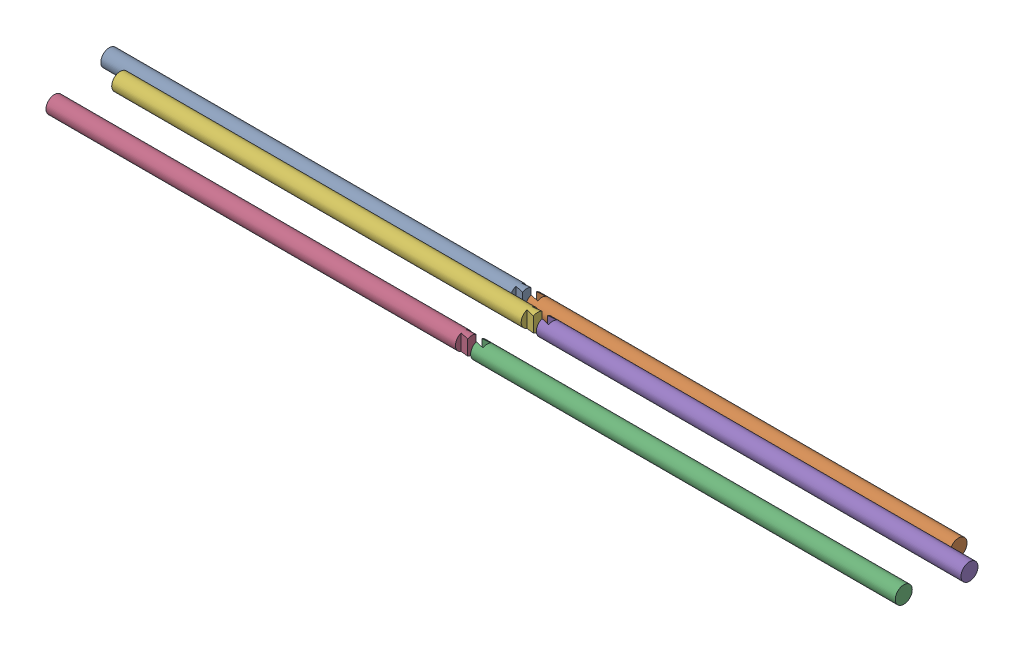
SolidWorks assembly Assem2, configuration Default. Lengths in mm.
Overall size (415.18 17.09 33.06).
4 component instances, 2 part files, 0 mates.
Components (placement in the parent):
- Axle without gear v01-1: Axle without gear v01 [Default] at (-212.7747 38.7586 85.9463) size (400 8 8)
- Assem3^Assem2-1: Assem3^Assem2 [Default] at (-12.5115 -8.6173 15.0041) size (400 8 8) (virtual)
  - Axle male-1: Axle male [Default] at (-201.0102 40.4552 95.9973) size (400 8 8)
- Axle male-1: Axle male [Default] at (-198.3463 40.9278 95.2177) size (400 8 8)
